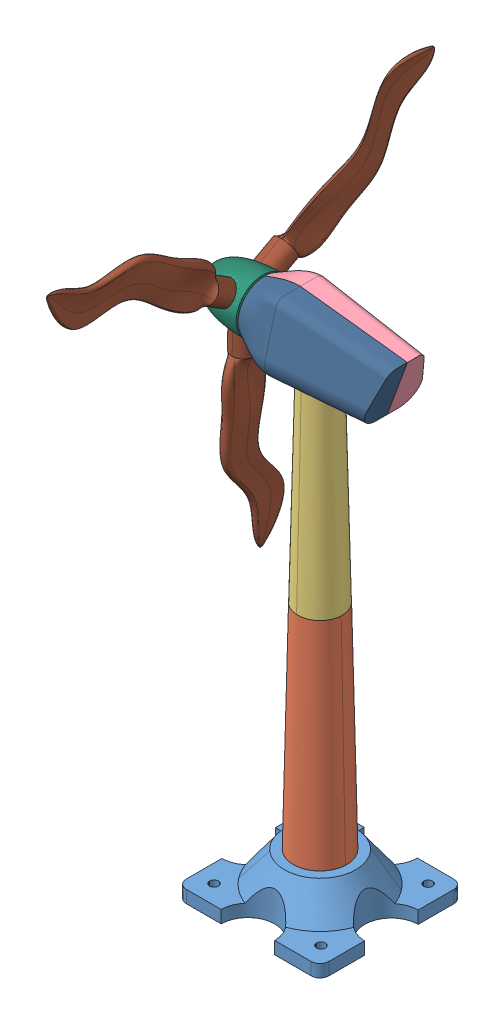
SolidWorks assembly Wind turbine assembly II , configuration Default. Lengths in mm.
Overall size (140.98 456.4 306.35).
17 component instances, 11 part files, 0 mates.
Components (placement in the parent):
- Wind turbine assembly MARC2(cordinate).STEP-1: Wind turbine assembly MARC2(cordinate).STEP [Default] at origin size (140.98 456.4 306.35)
  - base.STEP-1: base.STEP [Default] at (78.4995 -345.44 -0.2668) x (-0.000714 0 1) z (-1 0 -0.000714) size (101.6 30.48 101.6)
  - Wind turbine lower mast.STEP-1: Wind turbine lower mast.STEP [Default] at (78.4995 -327.66 -0.2668) x (0 1 0) z (0.998658 0 0.051782) size (165.1 38.1 38.1)
  - Wind turbine upper mast.STEP-1: Wind turbine upper mast.STEP [Default] at (78.74 -175.26 0) x (0 1 0) z (-0.998658 0 -0.051782) size (152.4 31.75 31.75)
  - nacelle.STEP-1: nacelle.STEP [Default] at (64.77 0 0) x (0 0 1) z (-1 0 0) size (25.51 48.27 101.62)
  - connecting rod.STEP-1: connecting rod.STEP [Default] at (78.74 -29.21 0) x (-0.653528 0 0.756902) z (-0.756902 0 -0.653528) size (9.53 38.1 9.53)
  - Turbine Hub.STEP-1: Turbine Hub.STEP [Default] x (0 -0.031407 -0.999507) z (-1 0 0) size (41.13 38.1 38.1)
  - Turbine Hub.STEP-2: Turbine Hub.STEP [Default] x (0 0.881302 0.472554) z (-1 0 0) size (41.13 38.1 38.1)
  - Turbine Hub.STEP-3: Turbine Hub.STEP [Default] x (0 -0.849895 0.526953) z (-1 0 0) size (41.13 38.1 38.1)
  - 2780T350_HIGH-LOAD BEARING_2780T35.STEP-1: 2780T350_HIGH-LOAD BEARING_2780T35.STEP [Default] at (64.9287 0 0) x (0 0.911809 0.410615) z (-1 0 0) size (23.02 23.02 7.94)
  - 2780T350_HIGH-LOAD BEARING_2780T35.STEP-2: 2780T350_HIGH-LOAD BEARING_2780T35.STEP [Default] at (109.3787 0 0) x (0 -0.378851 0.925458) z (-1 0 0) size (23.02 23.02 7.94)
  - Turbine main shaft.STEP-1: Turbine main shaft.STEP [Default] at (73.025 0 0) x (0 -0.627713 -0.778445) z (0 -0.778445 0.627713) size (9.53 95.25 9.53)
  - 98408A134_SIDE-MOUNT EXTERNAL RETAINING RING  E-STYLE_98408A134.STEP-1: 98408A134_SIDE-MOUNT EXTERNAL RETAINING RING  E-STYLE_98408A134.STEP [Default] at (116.9919 0 0) size (0.89 16.76 15.36)
  - Mirrornacelle.STEP-1: Mirrornacelle.STEP [Default] at (64.77 0 0) x (0 0 -1) z (1 0 0) size (25.53 48.36 101.62)
  - rundwa wing(1).STEP-1: rundwa wing(1).STEP [Default] at (25.4 4.0154 6.4762) x (1 0 0) z (0 -0.849895 0.526953) size (19.03 151.58 60.38)
  - rundwa wing(1).STEP-2: rundwa wing(1).STEP [Default] at (25.4 3.6009 -6.7155) x (1 0 0) z (0 0.881302 0.472554) size (19.03 151.58 60.38)
  - rundwa wing(1).STEP-3: rundwa wing(1).STEP [Default] at (25.4 -7.6162 0.2393) x (1 0 0) z (0 -0.031407 -0.999507) size (19.03 151.58 60.38)
